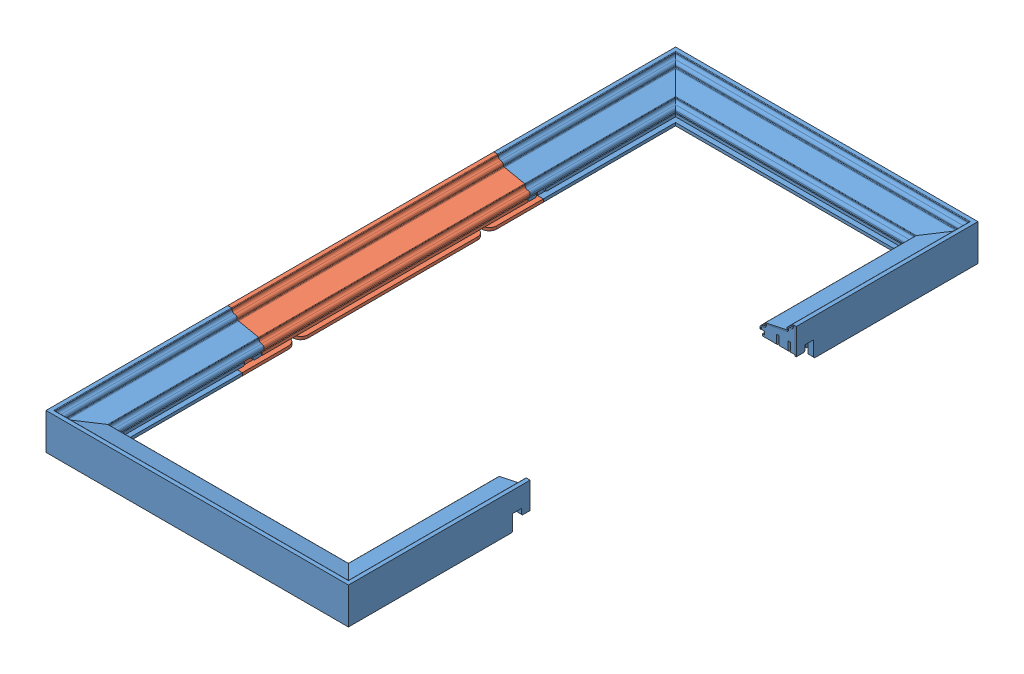
SolidWorks assembly little master, configuration Default. Lengths in mm.
Overall size (208 25 433).
3 component instances, 2 part files, 6 mates.
Components (placement in the parent):
- corner small-1: corner small [Default] at (-113.5317 21.7821 -80.761) size (208 25 125)
- ccenter height big-1: ccenter height big [Default] at (-113.5317 21.7821 32.239) size (25 25 207)
- corner small-2: corner small [Default] at (94.4683 21.7821 352.239) x (-1 0 0) z (0 0 -1) size (208 25 125)
Mates (geometry in assembly coordinates):
- Coincident1: coincident: plane of corner small-1 through (-109.5317 35.2821 44.239) normal (1 0 0); plane of ccenter height big-1 through (-109.5317 21.7821 32.239) normal (1 0 0)
- Coincident2: coincident: plane of corner small-1 through (-91.5317 32.8821 44.239) normal (0 -1 0); plane of ccenter height big-1 through (-91.5317 32.8821 239.239) normal (0 -1 0)
- Coincident3: coincident anti-aligned: plane of corner small-1 through (-88.5317 21.7821 38.239) normal (0 0 -1); plane of ccenter height big-1 through (-88.5317 21.7821 38.239) normal (0 0 1)
- Coincident4: coincident: plane of ccenter height big-1 through (-109.5317 21.7821 32.239) normal (1 0 0); plane of corner small-2 through (-109.5317 35.2821 239.204) normal (1 0 0)
- Coincident5: coincident: plane of ccenter height big-1 through (-91.5317 32.8821 239.239) normal (0 -1 0); plane of corner small-2 through (72.4683 32.8821 239.204) normal (0 -1 0)
- Coincident6: coincident anti-aligned: plane of ccenter height big-1 through (-88.5317 21.7821 233.239) normal (0 0 -1); plane of corner small-2 through (-88.5317 21.7821 245.204) normal (0 0 1)
